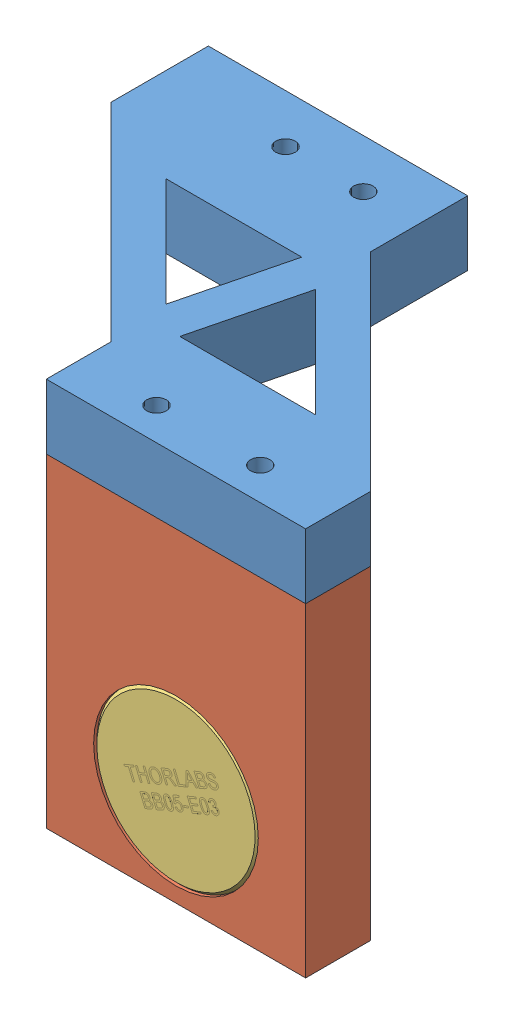
SolidWorks assembly arm, configuration Default. Lengths in mm.
Overall size (36 30.8 28.5).
3 component instances, 3 part files, 5 mates.
Components (placement in the parent):
- arm part1-1: arm part1 [Default] at (11.3756 1.7176 21.9737) size (36 5 28.5)
- arm part2-1: arm part2 [Default] at (14.2887 -30.1155 10.4991) size (20 25 5)
- BB05-E03-Solidworks-1: BB05-E03-Solidworks [Default] at (-48.8905 -39.0424 39.3094) x (-0.923728 -0.383049 0) z (0 0 -1) size (12.7 12.7 6)
Mates (geometry in assembly coordinates):
- Coincident1: coincident anti-aligned: plane of arm part1-1 through (11.3756 1.7176 21.9737) normal (0 -1 0); plane of arm part2-1 through (-9.7972 1.7176 15.4991) normal (0 1 0)
- Coincident2: coincident anti-aligned: line of arm part1-1 through (-9.7972 1.7176 15.4991) axis (1 0 0); line of arm part2-1 through (10.2028 1.7176 15.4991) axis (-1 0 0)
- Coincident3: coincident aligned: line of arm part1-1 through (10.2028 1.7176 15.4991) axis (0 0 -1); line of arm part2-1 through (10.2028 1.7176 15.4991) axis (0 0 -1)
- Coincident4: coincident aligned: plane of arm part2-1 through (14.2887 -30.1155 15.4991) normal (0 0 1); plane of BB05-E03-Solidworks-1 through (0.2028 -15.7824 15.4991) normal (0 0 1)
- Concentric1: concentric aligned: circle of arm part2-1; circle of BB05-E03-Solidworks-1
